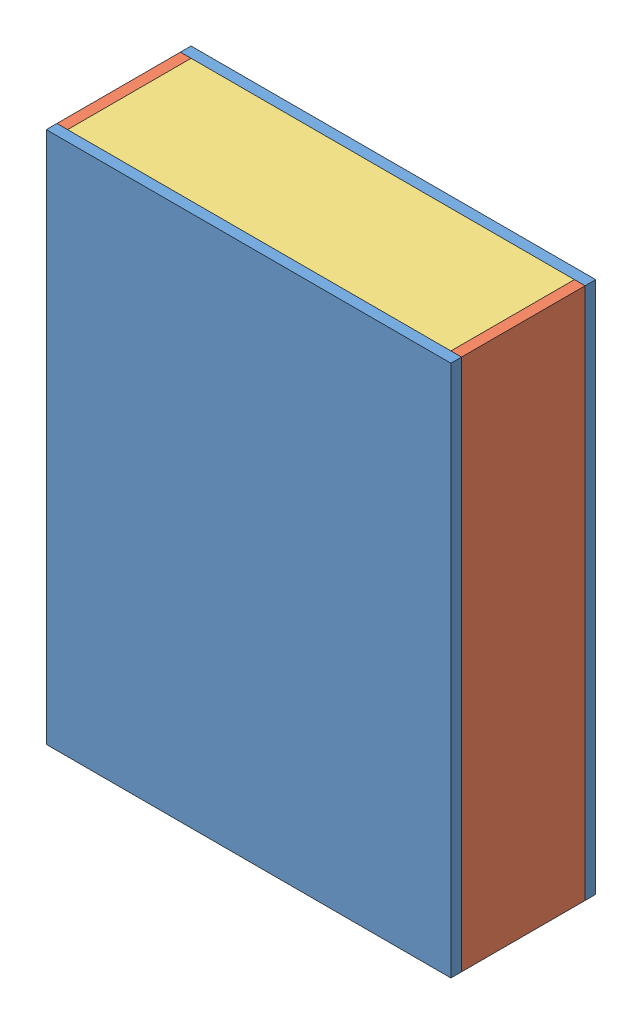
SolidWorks assembly Boite, configuration Défaut. Lengths in mm.
Overall size (190 250 68).
6 component instances, 3 part files, 16 mates.
Components (placement in the parent):
- FaceA-1: FaceA [Défaut] at (-143.168 -120.9591 250) size (190 250 5)
- FaceA-2: FaceA [Défaut] at (-143.168 -120.9591 313) size (190 250 5)
- FaceB-1: FaceB [Défaut] at (41.832 -120.9591 313) x (0 0 -1) z (1 0 0) size (58 250 5)
- FaceB-2: FaceB [Défaut] at (-143.168 -120.9591 313) x (0 0 -1) z (1 0 0) size (58 250 5)
- FaceHaut-1: FaceHaut [Défaut] at (41.832 124.0409 313) x (0 0 -1) z (0 1 0) size (58 180 5)
- FaceHaut-2: FaceHaut [Défaut] at (-138.168 -120.9591 255) x (0 0 1) z (0 1 0) size (58 180 5)
Mates (geometry in assembly coordinates):
- Coïncidente1: coincident anti-aligned: plane of FaceA-2 through (-143.168 -120.9591 313) normal (0 0 -1); plane of FaceB-1 through (46.832 129.0409 313) normal (0 0 1)
- Coïncidente2: coincident anti-aligned: line of FaceA-2 through (46.832 -120.9591 313) axis (0 1 0); line of FaceB-1 through (46.832 129.0409 313) axis (0 -1 0)
- Coïncidente3: coincident aligned: line of FaceA-2 through (46.832 129.0409 313) axis (-1 0 0); line of FaceB-1 through (46.832 129.0409 313) axis (-1 0 0)
- Coïncidente4: coincident anti-aligned: plane of FaceA-1 through (-143.168 -120.9591 255) normal (0 0 1); plane of FaceB-1 through (46.832 -120.9591 255) normal (0 0 -1)
- Coïncidente5: coincident aligned: line of FaceA-1 through (46.832 -120.9591 255) axis (0 1 0); line of FaceB-1 through (46.832 -120.9591 255) axis (0 1 0)
- Coïncidente6: coincident aligned: line of FaceA-1 through (46.832 129.0409 255) axis (-1 0 0); line of FaceB-1 through (46.832 129.0409 255) axis (-1 0 0)
- Coïncidente13: coincident anti-aligned: plane of FaceA-1 through (-143.168 -120.9591 255) normal (0 0 1); plane of FaceB-2 through (-138.168 -120.9591 255) normal (0 0 -1)
- Coïncidente15: coincident aligned: line of FaceA-2 through (-143.168 129.0409 313) axis (0 -1 0); line of FaceB-2 through (-143.168 129.0409 313) axis (0 -1 0)
- Coïncidente16: coincident: line of FaceA-2 through (46.832 129.0409 313) axis (-1 0 0); moEndPointRef_w of FaceB-2
- Coïncidente20: coincident anti-aligned: plane of FaceB-1 through (41.832 -120.9591 313) normal (-1 0 0); plane of FaceHaut-1 through (41.832 129.0409 255) normal (1 0 0)
- Coïncidente21: coincident anti-aligned: plane of FaceB-2 through (-138.168 -120.9591 313) normal (1 0 0); plane of FaceHaut-1 through (-138.168 129.0409 313) normal (-1 0 0)
- Coïncidente22: coincident aligned: line of FaceB-2 through (-138.168 129.0409 255) axis (0 0 1); line of FaceHaut-1 through (-138.168 129.0409 255) axis (0 0 1)
- Coïncidente23: coincident anti-aligned: line of FaceA-2 through (46.832 129.0409 313) axis (-1 0 0); line of FaceHaut-1 through (-138.168 129.0409 313) axis (1 0 0)
- Coïncidente24: coincident anti-aligned: plane of FaceA-1 through (-143.168 -120.9591 255) normal (0 0 1); plane of FaceHaut-2 through (-138.168 -115.9591 255) normal (0 0 -1)
- Coïncidente25: coincident anti-aligned: plane of FaceB-2 through (-138.168 -120.9591 313) normal (1 0 0); plane of FaceHaut-2 through (-138.168 -115.9591 313) normal (-1 0 0)
- Coïncidente26: coincident anti-aligned: line of FaceA-1 through (-143.168 -120.9591 255) axis (1 0 0); line of FaceHaut-2 through (41.832 -120.9591 255) axis (-1 0 0)
